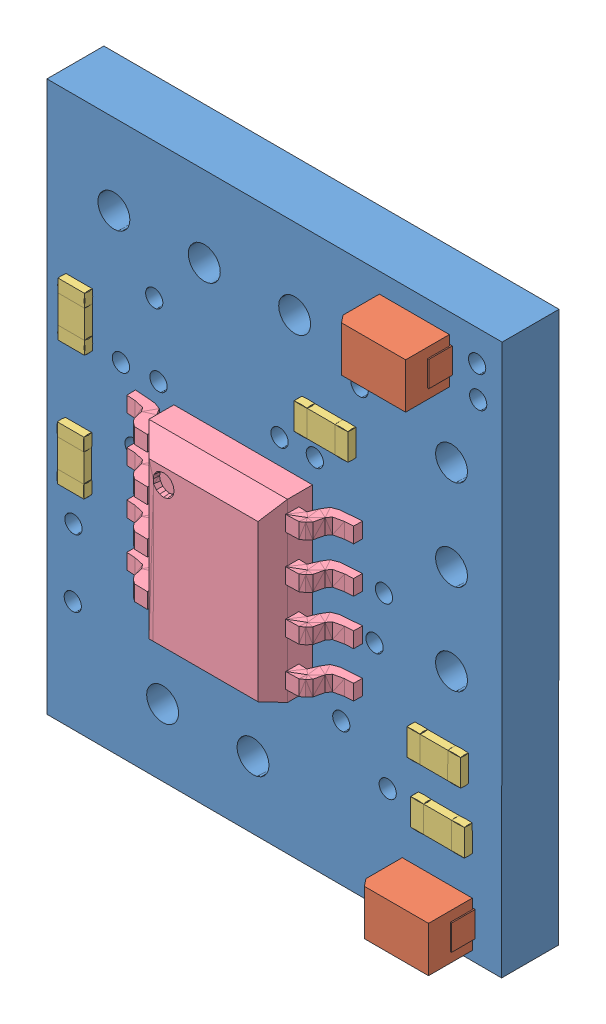
SolidWorks assembly microstart-cad, configuration Predeterminado. Lengths in mm.
Overall size (12.79 15.49 3.33).
9 component instances, 4 part files, 0 mates.
Components (placement in the parent):
- Board-1: Board [Predeterminado] at origin size (12.79 15.49 1.6)
- dio_0805-1: dio_0805 [Predeterminado] at (78.8867 44.7595 0) size (2.04 1.28 1.28)
- dio_0805-2: dio_0805 [Predeterminado] at (78.2434 58.152 0) size (2.04 1.28 1.28)
- res_0603-1: res_0603 [Predeterminado] at (75.8057 54.8117 0) x (-1 0 0) z (0 0 1) size (1.75 0.98 0.47)
- res_0603-2: res_0603 [Predeterminado] at (79.0787 46.8162 0) size (1.75 0.98 0.47)
- res_0603-3: res_0603 [Predeterminado] at (78.9746 48.4663 0) size (1.75 0.98 0.47)
- res_0603-4: res_0603 [Predeterminado] at (68.7881 54.0976 0) x (0 -1 0) z (0 0 1) size (1.75 0.98 0.47)
- res_0603-5: res_0603 [Predeterminado] at (68.769 50.5887 0) x (0 -1 0) z (0 0 1) size (1.75 0.98 0.47)
- soic-8_150mil-1: soic-8_150mil [Predeterminado] at (73.5882 50.8923 0) x (0 1 0) z (0 0 1) size (4.95 6.38 1.69)
